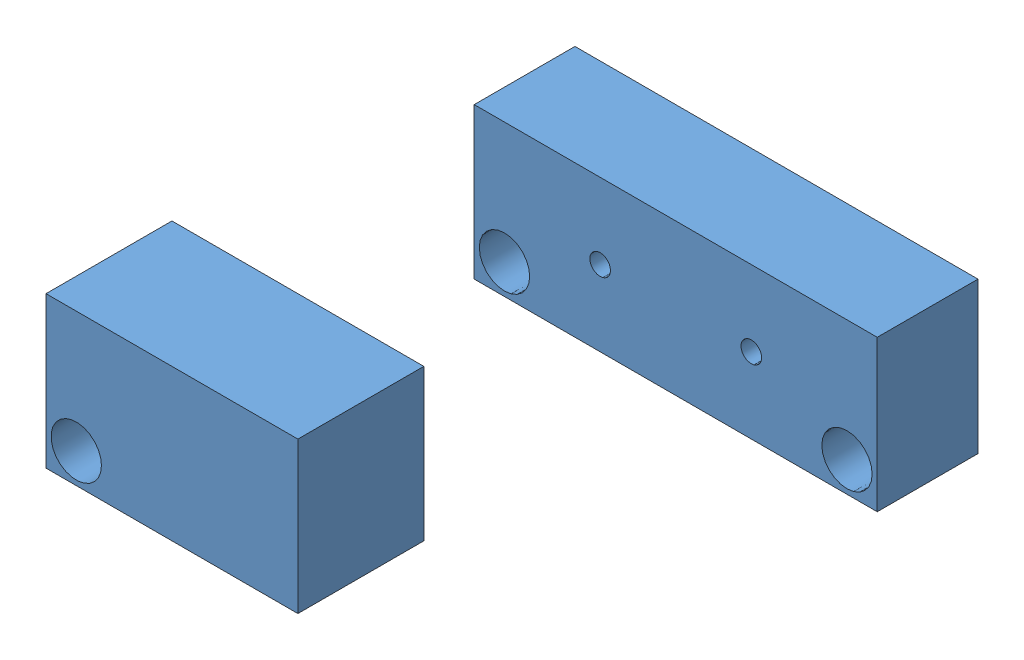
SolidWorks assembly TestAssembly1, configuration Default. Lengths in mm.
Overall size (180 60 190).
2 component instances, 1 part files, 2 mates.
Components (placement in the parent):
- TestPart1-3: TestPart1 [Default] at origin size (100 60 50)
- TestPart1-2: TestPart1 [name] at (20 0 -150) size (160 60 40)
Mates (geometry in assembly coordinates):
- mCoin: coincident: plane of TestPart1-3 through (0 60 0) normal (0 1 0); plane of TestPart1-2 through (20 60 -150) normal (0 1 0)
- mDist: distance = 100 mm: plane of TestPart1-2 through (20 60 -150) normal (0 0 1); plane of TestPart1-3 through (0 60 -50) normal (0 0 -1)
